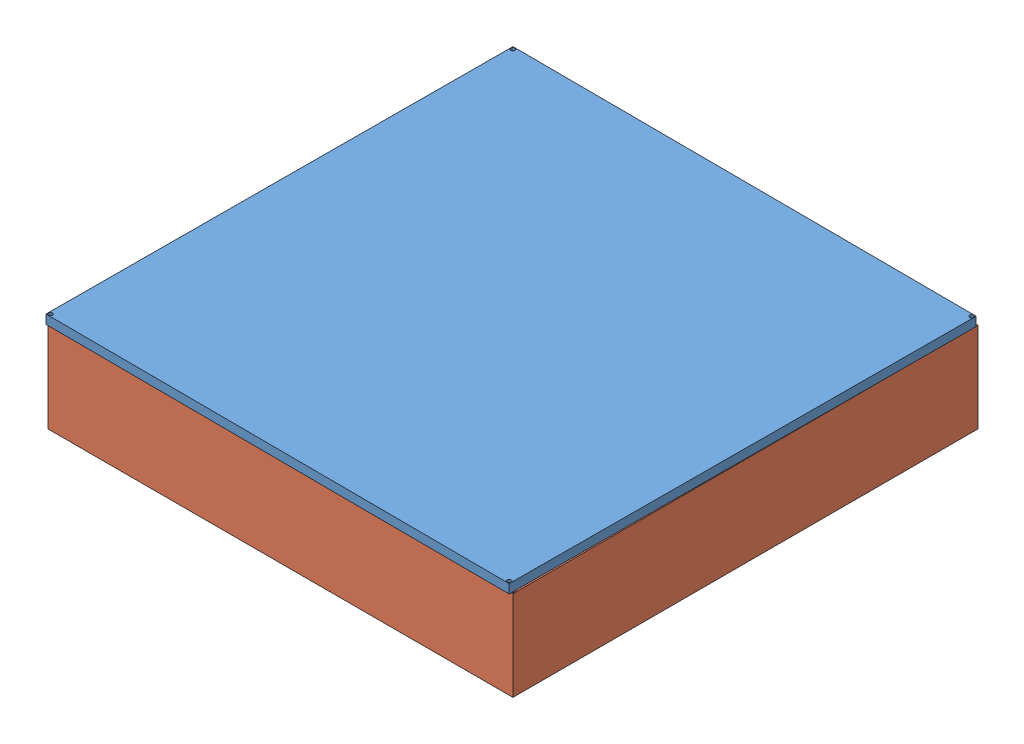
SolidWorks assembly watch case, configuration Default. Lengths in mm.
Overall size (52.01 11 52.03).
2 component instances, 2 part files, 2 mates.
Components (placement in the parent):
- base-1: base [Default] at (-10.3893 25.1882 33.0855) x (-0.004129 0 0.999991) z (0 -1 0) size (51.8 51.8 1)
- case-1: case [Default] at (-36.9898 4.1882 78.3929) size (51.8 10 51.8)
Mates (geometry in assembly coordinates):
- Coincident2: coincident anti-aligned: plane of base-1 through (-10.3893 24.1882 33.0855) normal (0 -1 0); plane of case-1 through (17.3868 24.1882 71.6166) normal (0 1 0)
- Concentric1: concentric aligned: circle of base-1; circle of case-1
